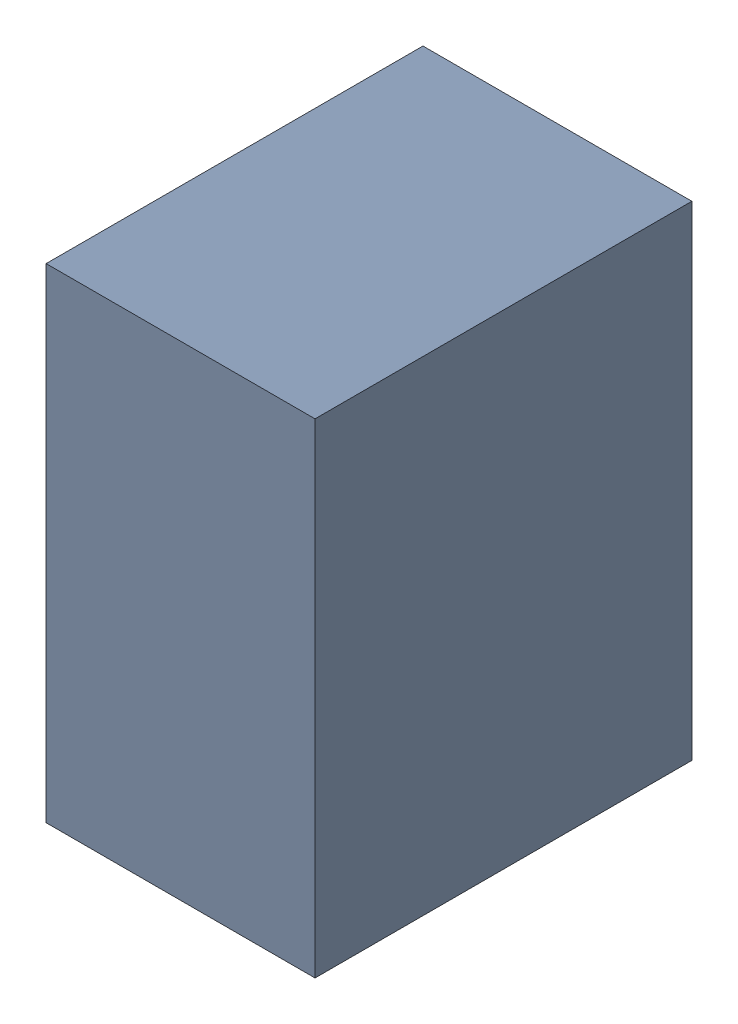
SolidWorks assembly C7, configuration Default. Lengths in mm.
Overall size (1 1.8 1.4).
3 component instances, 2 part files, 0 mates.
Components (placement in the parent):
- 1088883208-1: 1088883208 [Default] at (13.8 38.275 0) size (1 1.8 1.4)
  - Extruded-45-1: Extruded-45 [Default] at origin size (1 1.8 1.4)
- C0603-1: C0603 [Default] at (14.2001 37.475 0) x (0 1 0) z (1 0 0) size (1.6 0.5 0.8)
